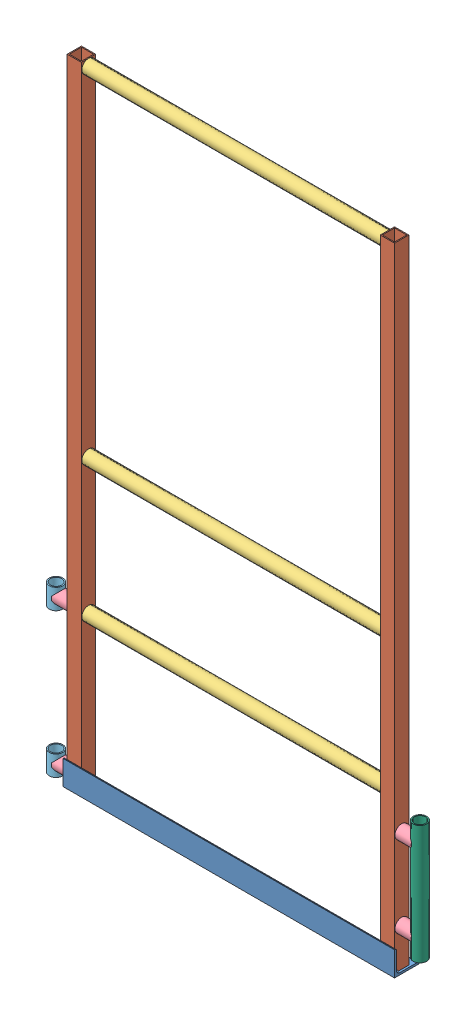
SolidWorks assembly GE-18011, configuration Default. Lengths in mm.
Overall size (1178.81 1981.2 76.2).
13 component instances, 6 part files, 42 mates.
Components (placement in the parent):
- GE-18011-01-1: GE-18011-01 [Default] at (-517.525 0 0) x (1 0 0) z (0 1 0) size (1035.05 76.2 76.2)
- GE-18011-02-1: GE-18011-02 [Default] at (-1501.775 0 0) x (1 0 0) z (0 1 0) size (44.45 44.45 1974.85)
- GE-18011-02-2: GE-18011-02 [Default] at (-523.875 0 0) x (1 0 0) z (0 1 0) size (44.45 44.45 1974.85)
- GE-18011-03-1: GE-18011-03 [Default] at (-523.875 1931.543 -1987.55) size (933.45 42.16 42.16)
- GE-18011-03-2: GE-18011-03 [Default] at (-523.875 875.157 -1987.55) size (933.45 42.16 42.16)
- GE-18011-03-3: GE-18011-03 [Default] at (-523.875 451.993 -1987.55) size (933.45 42.16 42.16)
- GE-18011-04-1: GE-18011-04 [Default] at (-511.175 0 -57.15) x (-1 0 0) z (0 1 0) size (50.8 42.16 42.16)
- GE-18011-04-2: GE-18011-04 [Default] at (-511.175 514.35 0) x (-1 0 0) z (0 -1 0) size (50.8 42.16 42.16)
- GE-18011-04-3: GE-18011-04 [Default] at (-523.875 347.218 0) x (1 0 0) z (0 1 0) size (50.8 42.16 42.16)
- GE-18011-04-4: GE-18011-04 [Default] at (-523.875 94.107 0) x (1 0 0) z (0 1 0) size (50.8 42.16 42.16)
- GE-18011-05-1: GE-18011-05 [Default] at (-511.175 450.85 -57.15) x (-1 0 0) z (0 1 0) size (42.16 42.16 63.5)
- GE-18011-05-2: GE-18011-05 [Default] at (-511.175 63.5 0) x (-1 0 0) z (0 -1 0) size (42.16 42.16 63.5)
- GE-18011-06-1: GE-18011-06 [Default] at (-517.525 438.15 -6.35) x (-1 0 0) z (0 -1 0) size (42.16 42.16 371.48)
Mates (geometry in assembly coordinates):
- Coincident1: coincident anti-aligned: plane of GE-18011-01-1 through (0 0 -38.1) normal (0 -1 0); plane of assembly through (0 0 0) normal (0 1 0)
- Coincident2: coincident aligned: plane of GE-18011-01-1 through (0 38.1 0) normal (0 0 1); plane of assembly through (0 0 0) normal (0 0 1)
- Coincident3: coincident aligned: plane of GE-18011-01-1 through (0 38.1 -38.1) normal (1 0 0); plane of assembly through (0 0 0) normal (1 0 0)
- Coincident4: coincident anti-aligned: plane of GE-18011-01-1 through (0 6.35 -41.275) normal (0 1 0); plane of GE-18011-02-2 through (-50.8 6.35 -41.275) normal (0 -1 0)
- Distance1: distance = 6.35 mm aligned: plane of GE-18011-02-2 through (-6.35 990.6 -38.1) normal (1 0 0); plane of GE-18011-01-1 through (0 38.1 -38.1) normal (1 0 0)
- Coincident6: coincident anti-aligned: plane of GE-18011-01-1 through (0 41.275 -6.35) normal (0 0 -1); plane of GE-18011-02-2 through (-50.8 87.0439 -6.35) normal (0 0 1)
- Coincident7: coincident anti-aligned: plane of GE-18011-01-1 through (0 6.35 -41.275) normal (0 1 0); plane of GE-18011-02-1 through (-1028.7 6.35 -41.275) normal (0 -1 0)
- Distance2: distance = 6.35 mm aligned: plane of GE-18011-02-1 through (-1028.7 990.6 -38.1) normal (-1 0 0); plane of GE-18011-01-1 through (-1035.05 38.1 -38.1) normal (-1 0 0)
- Coincident9: coincident anti-aligned: plane of GE-18011-01-1 through (0 41.275 -6.35) normal (0 0 -1); plane of GE-18011-02-1 through (-1028.7 87.0439 -6.35) normal (0 0 1)
- Coincident10: coincident anti-aligned: plane of GE-18011-02-2 through (-50.8 990.6 -38.1) normal (-1 0 0); plane of GE-18011-03-3 through (-50.8 490.093 -996.95) normal (1 0 0)
- Distance3: distance = 480.568 mm: cylinder of GE-18011-03-3 through (-50.798 480.568 -28.575) axis (1 0 0) radius 21.082; plane of GE-18011-01-1 through (0 0 -38.1) normal (0 -1 0)
- Distance4: distance = 22.225 mm: plane of GE-18011-02-2 through (-50.8 87.0439 -6.35) normal (0 0 1); cylinder of GE-18011-03-3 through (-50.798 480.568 -28.575) axis (1 0 0) radius 21.082
- Coincident11: coincident anti-aligned: plane of GE-18011-02-2 through (-50.8 990.6 -38.1) normal (-1 0 0); plane of GE-18011-03-2 through (-50.8 913.257 -996.95) normal (1 0 0)
- Distance5: distance = 22.225 mm: cylinder of GE-18011-03-2 through (-50.798 903.732 -28.575) axis (1 0 0) radius 21.082; plane of GE-18011-02-2 through (-50.8 87.0439 -6.35) normal (0 0 1)
- Distance6: distance = 903.732 mm: cylinder of GE-18011-03-2 through (-50.798 903.732 -28.575) axis (1 0 0) radius 21.082; plane of GE-18011-01-1 through (0 0 -38.1) normal (0 -1 0)
- Coincident12: coincident anti-aligned: plane of GE-18011-02-2 through (-50.8 990.6 -38.1) normal (-1 0 0); plane of GE-18011-03-1 through (-50.8 1969.643 -996.95) normal (1 0 0)
- Distance7: distance = 22.225 mm: cylinder of GE-18011-03-1 through (-50.798 1960.118 -28.575) axis (1 0 0) radius 21.082; plane of GE-18011-02-2 through (-50.8 87.0439 -6.35) normal (0 0 1)
- Tangent6: tangent aligned: plane of GE-18011-02-2 through (-50.8 1981.2 -28.8192) normal (0 1 0); cylinder of GE-18011-03-1 through (-50.798 1960.118 -28.575) axis (1 0 0) radius 21.082
- Parallel1: parallel aligned: plane of GE-18011-03-1 through (-523.875 1931.543 -1987.55) normal (0 1 0); plane of assembly through (0 0 0) normal (0 1 0)
- Parallel2: parallel aligned: plane of GE-18011-03-2 through (-523.875 875.157 -1987.55) normal (0 1 0); plane of assembly through (0 0 0) normal (0 1 0)
- Parallel3: parallel aligned: plane of GE-18011-03-3 through (-523.875 451.993 -1987.55) normal (0 1 0); plane of assembly through (0 0 0) normal (0 1 0)
- Coincident16: coincident anti-aligned: plane of GE-18011-02-1 through (-1028.7 990.6 -38.1) normal (-1 0 0); plane of GE-18011-04-2 through (-1028.7 -479.425 -28.575) normal (1 0 0)
- Distance8: distance = 22.225 mm: cylinder of GE-18011-04-2 through (-1079.5 482.6 -28.575) axis (-1 0 0) radius 21.082; plane of GE-18011-02-2 through (-50.8 87.0439 -6.35) normal (0 0 1)
- Coincident17: coincident anti-aligned: plane of GE-18011-02-1 through (-1028.7 990.6 -38.1) normal (-1 0 0); plane of GE-18011-04-1 through (-1028.7 993.775 -28.575) normal (1 0 0)
- Distance9: distance = 22.225 mm: cylinder of GE-18011-04-1 through (-1079.5 31.75 -28.575) axis (-1 0 0) radius 21.082; plane of GE-18011-02-2 through (-50.8 87.0439 -6.35) normal (0 0 1)
- Parallel4: parallel anti-aligned: plane of GE-18011-01-1 through (0 0 -38.1) normal (0 -1 0); plane of GE-18011-04-1 through (-511.175 0 -57.15) normal (0 1 0)
- Concentric1: concentric anti-aligned: cylinder of GE-18011-04-1 through (-1085.85 76.2 -28.575) axis (0 1 0) radius 21.082; cylinder of GE-18011-05-2 through (-1085.85 0 -28.575) axis (0 -1 0) radius 21.082
- Coincident19: coincident aligned: plane of GE-18011-01-1 through (0 0 -38.1) normal (0 -1 0); plane of GE-18011-05-2 through (-550.291 0 -38.1) normal (0 -1 0)
- Concentric2: concentric anti-aligned: cylinder of GE-18011-05-1 through (-1085.85 514.35 -28.575) axis (0 1 0) radius 21.082; cylinder of GE-18011-05-2 through (-1085.85 0 -28.575) axis (0 -1 0) radius 21.082
- Distance11: distance = 450.85 mm aligned: plane of GE-18011-05-1 through (-550.291 450.85 -19.05) normal (0 -1 0); plane of GE-18011-01-1 through (0 0 -38.1) normal (0 -1 0)
- Distance13: distance = 31.75 mm: plane of GE-18011-05-2 through (-550.291 63.5 -38.1) normal (0 1 0); cylinder of GE-18011-04-1 through (-1079.5 31.75 -28.575) axis (-1 0 0) radius 17.526
- Parallel5: parallel anti-aligned: cylinder of GE-18011-04-2 through (-1085.85 438.15 -28.575) axis (0 -1 0) radius 21.082; cylinder of GE-18011-05-1 through (-1085.85 514.35 -28.575) axis (0 1 0) radius 21.082
- Distance14: distance = 31.75 mm: cylinder of GE-18011-04-2 through (-1079.5 482.6 -28.575) axis (-1 0 0) radius 17.526; plane of GE-18011-05-1 through (-550.291 514.35 -19.05) normal (0 1 0)
- Coincident21: coincident anti-aligned: plane of GE-18011-02-2 through (-6.35 990.6 -38.1) normal (1 0 0); plane of GE-18011-04-4 through (-6.35 1087.882 -28.575) normal (-1 0 0)
- Distance15: distance = 22.225 mm: cylinder of GE-18011-04-4 through (44.45 125.857 -28.575) axis (1 0 0) radius 21.082; plane of GE-18011-02-1 through (-1028.7 87.0439 -6.35) normal (0 0 1)
- Coincident22: coincident anti-aligned: plane of GE-18011-02-2 through (-6.35 990.6 -38.1) normal (1 0 0); plane of GE-18011-04-3 through (-6.35 1340.993 -28.575) normal (-1 0 0)
- Distance16: distance = 22.225 mm: plane of GE-18011-02-1 through (-1028.7 87.0439 -6.35) normal (0 0 1); cylinder of GE-18011-04-3 through (44.45 378.968 -28.575) axis (1 0 0) radius 21.082
- Distance17: distance = 66.675 mm aligned: plane of GE-18011-06-1 through (-481.584 66.675 -44.45) normal (0 -1 0); plane of GE-18011-01-1 through (0 0 -38.1) normal (0 -1 0)
- Concentric4: concentric anti-aligned: cylinder of GE-18011-04-4 through (50.8 170.307 -28.575) axis (0 1 0) radius 21.082; cylinder of GE-18011-06-1 through (50.8 66.675 -28.575) axis (0 -1 0) radius 21.082
- Parallel6: parallel anti-aligned: cylinder of GE-18011-04-3 through (-1085.85 423.418 -28.575) axis (0 1 0) radius 21.082; cylinder of GE-18011-06-1 through (50.8 66.675 -28.575) axis (0 -1 0) radius 21.082
- Distance18: distance = 38.1 mm: cylinder of GE-18011-04-4 through (44.45 125.857 -28.575) axis (1 0 0) radius 21.082; plane of GE-18011-06-1 through (-481.584 66.675 -44.45) normal (0 -1 0)
- Distance19: distance = 38.1 mm: cylinder of GE-18011-04-3 through (44.45 378.968 -28.575) axis (1 0 0) radius 21.082; plane of GE-18011-06-1 through (-481.584 438.15 -44.45) normal (0 1 0)
